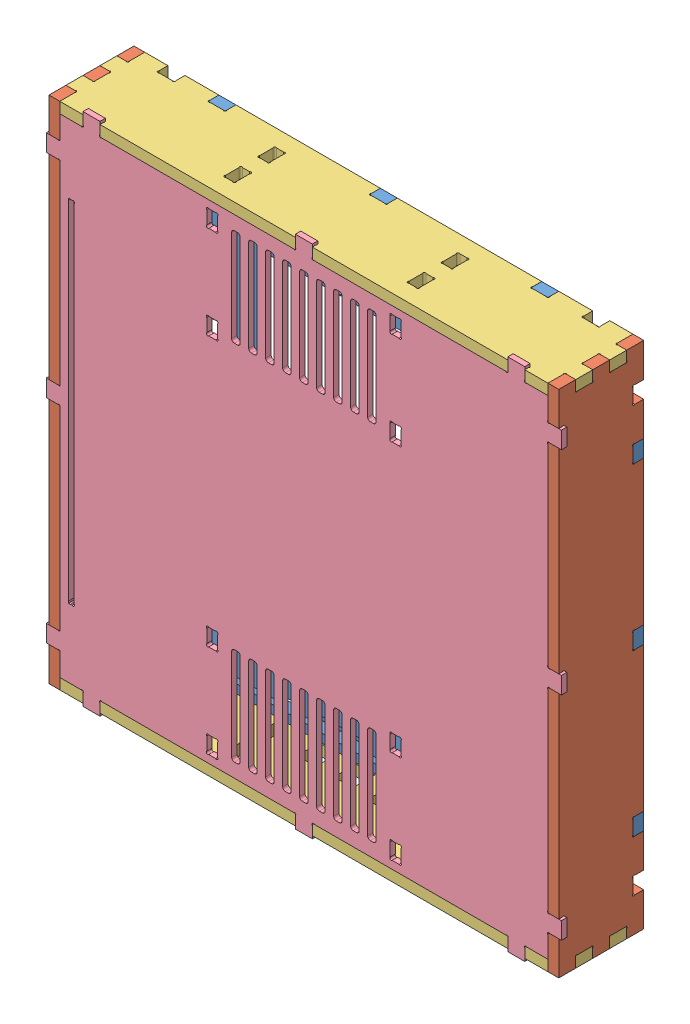
SolidWorks assembly brain_assembly, configuration Default. Lengths in mm.
Overall size (303.17 303.18 50).
6 component instances, 4 part files, 16 mates.
Components (placement in the parent):
- pvc-025-brain02-2: pvc-025-brain02 [Default] at (-135.6596 53.2768 260.8986) size (300 300 6.35)
- pvc-025-brain03-1: pvc-025-brain03 [Default] at (-135.6596 46.9268 254.5486) x (0 0 1) z (-1 0 0) size (50 300 6.35)
- pvc-025-brain05-1: pvc-025-brain05 [Default] at (-142.0096 340.5768 294.5486) x (1 0 0) z (0 1 0) size (300 50 6.35)
- pvc-025-brain03-2: pvc-025-brain03 [Default] at (157.9904 46.9268 254.5486) x (0 0 1) z (-1 0 0) size (50 300 6.35)
- pvc-025-brain05-2: pvc-025-brain05 [slotted] at (-142.0096 46.9268 294.5486) x (1 0 0) z (0 1 0) size (300 50 6.35)
- pvc-025-brain07-1: pvc-025-brain07 [Default] at (151.6404 53.2768 304.5486) x (-1 0 0) z (0 0 -1) size (303.17 303.17 3.17)
Mates (geometry in assembly coordinates):
- Coincident2: coincident: plane of assembly; plane of assembly; plane of pvc-025-brain02-2 through (-135.6596 340.5768 254.5486) normal (0 1 0); plane of pvc-025-brain05-1 through (137.4291 340.5768 301.9348) normal (0 -1 0)
- Coincident4: coincident: plane of assembly; plane of assembly; plane of pvc-025-brain02-2 through (151.6404 340.5768 254.5486) normal (1 0 0); plane of pvc-025-brain03-2 through (151.6404 67.4881 260.3373) normal (-1 0 0)
- Coincident5: coincident: plane of assembly; plane of assembly; plane of pvc-025-brain02-2 through (152.2017 297.4881 254.5486) normal (0 0 -1); plane of pvc-025-brain03-1 through (-142.0096 286.9268 254.5486) normal (0 0 -1)
- Coincident7: coincident: plane of assembly; plane of assembly; plane of pvc-025-brain02-2 through (-135.6596 203.0493 254.5486) normal (-1 0 0); plane of pvc-025-brain03-1 through (-135.6596 67.4881 260.3373) normal (1 0 0)
- Coincident8: coincident: plane of assembly; plane of assembly; plane of pvc-025-brain02-2 through (-135.6596 340.5768 254.5486) normal (0 1 0); plane of pvc-025-brain03-1 through (-142.0096 340.5768 273.426) normal (0 1 0)
- Coincident9: coincident: plane of assembly; plane of assembly; plane of pvc-025-brain02-2 through (152.2017 297.4881 254.5486) normal (0 0 -1); plane of pvc-025-brain03-2 through (151.6404 191.9268 254.5486) normal (0 0 -1)
- Coincident10: coincident: plane of assembly; plane of assembly; plane of pvc-025-brain02-2 through (151.6404 53.2768 254.5486) normal (0 -1 0); plane of pvc-025-brain03-2 through (151.6404 53.2768 265.6711) normal (0 -1 0)
- Coincident11: coincident: plane of assembly; plane of assembly; plane of pvc-025-brain02-2 through (151.6404 95.8043 254.5486) normal (1 0 0); plane of pvc-025-brain03-2 through (151.6404 67.4881 260.3373) normal (-1 0 0)
- Coincident12: coincident: plane of assembly; plane of assembly; plane of pvc-025-brain02-2 through (152.2017 297.4881 260.8986) normal (0 0 1); plane of pvc-025-brain05-1 through (99.1129 346.9268 260.8986) normal (0 0 -1)
- Coincident13: coincident: plane of assembly; plane of assembly; plane of pvc-025-brain02-2 through (151.6404 340.5768 254.5486) normal (1 0 0); plane of pvc-025-brain05-1 through (151.6404 346.9268 275.6711) normal (1 0 0)
- Coincident15: coincident: plane of assembly; plane of assembly; plane of pvc-025-brain03-2 through (151.6404 67.4881 260.3373) normal (-1 0 0); plane of pvc-025-brain05-2 through (151.6404 53.2768 254.5486) normal (1 0 0)
- Coincident17: coincident: plane of assembly; plane of assembly; plane of pvc-025-brain02-2 through (152.2017 297.4881 260.8986) normal (0 0 1); plane of pvc-025-brain05-2 through (99.1129 53.2768 260.8986) normal (0 0 -1)
- Coincident19: coincident: plane of assembly; plane of assembly; plane of pvc-025-brain02-2 through (96.8679 53.2768 254.5486) normal (0 -1 0); plane of pvc-025-brain05-2 through (137.4291 53.2768 301.9348) normal (0 1 0)
- Coincident20: coincident: plane of assembly; plane of assembly; plane of pvc-025-brain03-1 through (-135.6596 67.4881 260.3373) normal (1 0 0); plane of pvc-025-brain07-1 through (-135.6596 78.0493 301.3736) normal (-1 0 0)
- Coincident21: coincident: plane of assembly; plane of assembly; plane of pvc-025-brain03-1 through (-142.0096 68.0493 301.3736) normal (0 0 1); plane of pvc-025-brain07-1 through (138.5517 341.1381 301.3736) normal (0 0 -1)
- Coincident23: coincident: plane of assembly; plane of assembly; plane of pvc-025-brain02-2 through (-129.2904 93.7518 254.5486) normal (0 1 0); plane of pvc-025-brain07-1 through (-129.2904 93.7518 301.3736) normal (0 1 0)
